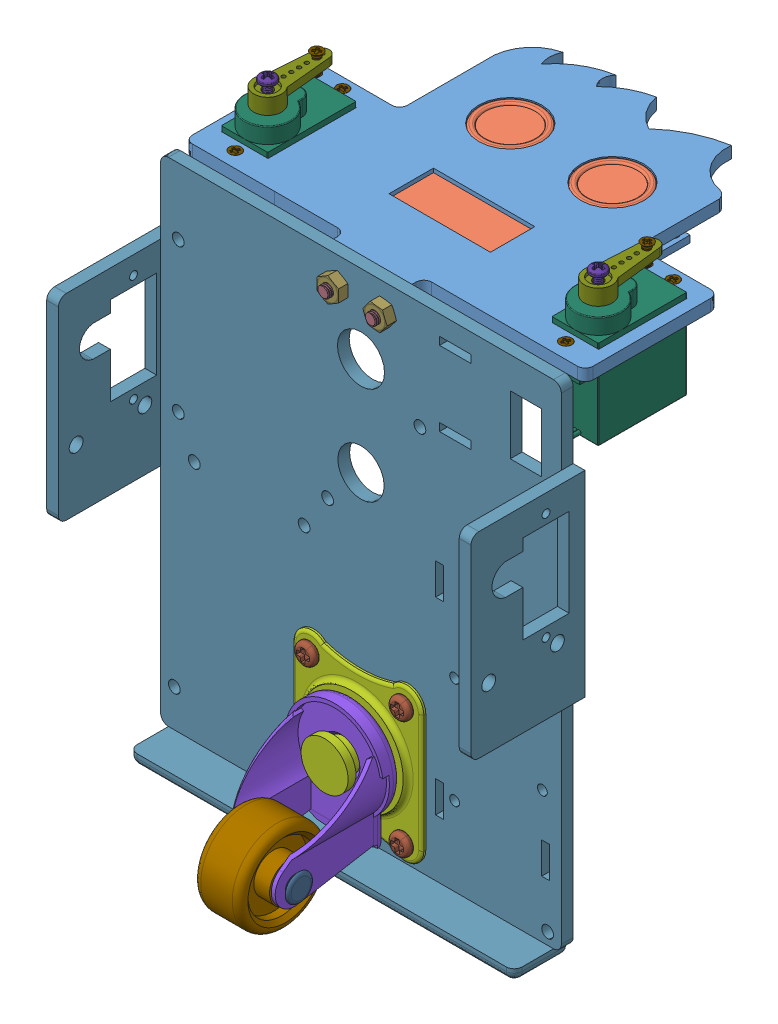
SolidWorks assembly DYOR_3D_OL_AC, configuration Predeterminado. Lengths in mm.
Overall size (108 144.05 112.97).
66 component instances, 23 part files, 16 mates.
Components (placement in the parent):
- HC-SR04 Ping Sensor-1: HC-SR04 Ping Sensor [Default] at (9.418 28.7888 -38.4615) x (0 0 -1) z (0 1 0) size (25.18 45 18.07)
  - PCB-1: PCB [Default] at origin size (20.5 45 1.75)
  - Transducer-1: Transducer [Default] at (0 -13 13.25) x (1 0 0) z (0 -1 0) size (15.88 12 15.88)
  - Transducer-2: Transducer [Default] at (0 13 13.25) x (1 0 0) z (0 -1 0) size (15.88 12 15.88)
  - 3 Pin Header 90 Degree-1: 3 Pin Header 90 Degree [Default] at (8.4275 0 -1.25) x (-1 0 0) z (0 -1 0) size (8 7.82 10)
  - 14 Pin SMT-1: 14 Pin SMT [Default] at (-0.35 -18.5 -0.85) x (0 -1 0) z (1 0 0) size (6 1.6 8.8)
  - 14 Pin SMT-2: 14 Pin SMT [Default] at (0 -0.3826 -0.85) x (1 0 0) z (0 1 0) size (6 1.6 8.8)
  - 14 Pin SMT-3: 14 Pin SMT [Default] at (0 17.5274 -0.85) x (1 0 0) z (0 1 0) size (6 1.6 8.8)
  - Cap1 SMT-1: Cap1 SMT [Default] at (-1.755 7.4774 -0.9689) x (0 1 0) z (-1 0 0) size (4.5 1.84 1.75)
  - Cap1 SMT-2: Cap1 SMT [Default] at (6.835 7.4774 -0.9689) x (0 1 0) z (-1 0 0) size (4.5 1.84 1.75)
  - Cap1 SMT-3: Cap1 SMT [Default] at (-6.835 7.4774 -0.9689) x (0 1 0) z (-1 0 0) size (4.5 1.84 1.75)
  - Cap1 SMT-4: Cap1 SMT [Default] at (4.295 7.4774 -0.9689) x (0 1 0) z (-1 0 0) size (4.5 1.84 1.75)
  - Cap1 SMT-5: Cap1 SMT [Default] at (1.755 7.4774 -0.9689) x (0 1 0) z (-1 0 0) size (4.5 1.84 1.75)
  - Cap1 SMT-6: Cap1 SMT [Default] at (-4.295 7.4774 -0.9689) x (0 1 0) z (-1 0 0) size (4.5 1.84 1.75)
  - HC-SR04 Crystal-1: HC-SR04 Crystal [Default] at (-8.3 0 1.75) x (0 -1 0) z (0 0 1) size (10 3.5 2.7)
- CA-1: CA [Predeterminado] at (-2.207 18.0036 0) size (33 45.94 43.2)
  - Caster Wheel-1: Caster Wheel [Default] at (57.6387 -78.841 57.7572) x (0 1 0) z (-1 0 0) size (45.94 37.59 33)
    - caster holder-1: caster holder [Default] at (-24.0751 44.7184 29.5137) x (1 0 0) z (0 0 -1) size (39 9.27 33)
    - holder-1: holder [Default] at (-1.5751 42.9484 46.0137) x (0 0 1) z (1 0 0) size (25 28.07 31.31)
    - caster wheel-1: caster wheel [Default] at (-15.6961 19.9484 46.0137) x (0.997275 0.073773 0) z (0 0 1) size (23 23 14)
    - Part4-1: Part4 [Default] at (-15.6961 19.9484 55.0137) x (-0.978448 0.206495 0) z (0 0 -1) size (7 7 20)
  - M3x6 Philips Screw-1: M3x6 Philips Screw [Predeterminado] at (23.625 -65.4161 13.5389) size (5.3 5.3 7.81)
  - M3x6 Philips Screw-2: M3x6 Philips Screw [Predeterminado] at (-0.375 -65.4161 13.5389) size (5.3 5.3 7.81)
  - M3x6 Philips Screw-3: M3x6 Philips Screw [Predeterminado] at (-0.375 -95.4161 13.5389) size (5.3 5.3 7.81)
  - M3x6 Philips Screw-4: M3x6 Philips Screw [Predeterminado] at (23.625 -95.4161 13.5389) size (5.3 5.3 7.81)
  - M3 Nut-1: M3 Nut [Predeterminado] at (23.625 -65.4161 11.0389) size (6.27 6.27 2.71)
  - M3 Nut-2: M3 Nut [Predeterminado] at (-0.375 -65.4161 11.0389) size (6.27 6.27 2.71)
  - M3 Nut-3: M3 Nut [Predeterminado] at (-0.375 -95.4161 11.0389) size (6.27 6.27 2.71)
  - M3 Nut-4: M3 Nut [Predeterminado] at (23.625 -95.4161 11.0389) size (6.27 6.27 2.71)
- M3x10 Philips Screw-2: M3x10 Philips Screw [Predeterminado] at (3.418 36.0388 6.1705) x (-0.582954 -0.812505 0) z (0 0 -1) size (5.3 5.3 11.8)
- M3x10 Philips Screw-3: M3x10 Philips Screw [Predeterminado] at (15.418 36.0388 6.1705) x (-0.89856 -0.438851 0) z (0 0 -1) size (5.3 5.3 11.8)
- M3 Nut-1: M3 Nut [Predeterminado] at (3.418 36.0388 16.5389) size (6.27 6.27 2.71)
- M3 Nut-2: M3 Nut [Predeterminado] at (15.418 36.0388 11.0389) x (-0.923728 -0.383049 0) z (0 0 -1) size (6.27 6.27 2.71)
- Base-1: Base [Predeterminado] at (60.418 -80.9125 12.5389) size (108 128.45 29)
- AC-1: AC [Predeterminado] at (-137.3228 216.8523 -134.1392) size (95.94 34.06 31.9)
  - sg90-1: sg90 [Default] at (182.9409 -195.7135 134.2781) x (0 0 -1) z (1 0 0) size (31.9 29.9 11.8)
  - sg90-2: sg90 [Default] at (98.7972 -195.7135 134.2781) x (0 0 -1) z (1 0 0) size (31.9 29.9 11.8)
  - SG90 plastic Horn-1: SG90 plastic Horn [Default] at (188.8409 -166.2635 128.3781) x (-0.029359 0 -0.999569) z (0.999569 0 -0.029359) size (19.4 4 7.07)
  - SG90 plastic Horn-2: SG90 plastic Horn [Default] at (104.6972 -166.2635 128.3781) x (-0.012387 0 -0.999923) z (0.999923 0 -0.012387) size (19.4 4 7.07)
  - (M2_3_mm)_90116A007_METRIC 316 SS PAN HEAD PHILLIPS MACHINE SCREW-1: (M2_3_mm)_90116A007_METRIC 316 SS PAN HEAD PHILLIPS MACHINE SCREW [90116A007] at (104.6972 -166.2635 128.3781) x (-1 0 0) z (0 1 0) size (4 4 4.68)
  - (M2_3_mm)_90116A007_METRIC 316 SS PAN HEAD PHILLIPS MACHINE SCREW-2: (M2_3_mm)_90116A007_METRIC 316 SS PAN HEAD PHILLIPS MACHINE SCREW [90116A007] at (188.8409 -166.2635 128.3781) x (-1 0 0) z (0 1 0) size (4 4 4.68)
  - M2x6 SelfTap Screw-1: M2x6 SelfTap Screw [Predeterminado] at (104.6972 -162.7635 115.8781) x (0.825172 0 -0.564882) z (0 1 0) size (3.4 3.28 6)
  - M2x6 SelfTap Screw-2: M2x6 SelfTap Screw [Predeterminado] at (188.7787 -162.7635 115.8783) x (0.001298 0 -0.999999) z (0 1 0) size (3.4 3.28 6)
  - M2x6 SelfTap Screw-3: M2x6 SelfTap Screw [Predeterminado] at (104.6972 -174.3135 109.3781) x (-0.923728 0 -0.383049) z (0 1 0) size (3.4 3.28 6)
  - M2x6 SelfTap Screw-4: M2x6 SelfTap Screw [Predeterminado] at (104.6972 -174.3135 136.6781) x (-0.923728 0 -0.383049) z (0 1 0) size (3.4 3.28 6)
  - M2x6 SelfTap Screw-5: M2x6 SelfTap Screw [Predeterminado] at (188.8409 -174.3135 136.6781) x (0.923728 0 0.383049) z (0 1 0) size (3.4 3.28 6)
  - M2x6 SelfTap Screw-6: M2x6 SelfTap Screw [Predeterminado] at (188.8409 -174.3135 109.3781) x (0.923728 0 0.383049) z (0 1 0) size (3.4 3.28 6)
- Front_OL_AC-1: Front_OL_AC [Predeterminado] at (-51.1718 39.5388 -46.4823) x (1 0 0) z (0 1 0) size (101.94 72.38 11)
- OLED_0.91_128x32-1: OLED_0.91_128x32 [Predeterminado] at (10.618 39.0288 -13.1554) x (1 0 0) z (0 1 0) size (38.3 12.1 11.46)
  - OLED_0.91_128x32.stp-1: OLED_0.91_128x32.stp [Predeterminado] at origin size (38.3 12.1 11.46)
    - OLED_0.91_128x32.stp-1: OLED_0.91_128x32.stp [Predeterminado] at origin size (38.3 12.1 2.57)
    - Pin Header 4 x 1 TH 2.54mm Pitch.stp-1: Pin Header 4 x 1 TH 2.54mm Pitch.stp [Predeterminado] at (-17.55 -3.81 -2.6) size (2.54 10.16 11.43)
    - RESC-0603.stp-1: RESC-0603.stp [Predeterminado] at (4.3 -5.3 0) x (1 0 0) z (0 0 -1) size (1.7 0.9 0.55)
    - RESC-0603.stp-2: RESC-0603.stp [Predeterminado] at (4.3 -3.8 0) x (1 0 0) z (0 0 -1) size (1.7 0.9 0.55)
    - RESC-0603.stp-3: RESC-0603.stp [Predeterminado] at (4.3 -2.3 0) x (1 0 0) z (0 0 -1) size (1.7 0.9 0.55)
    - RESC-0603.stp-4: RESC-0603.stp [Predeterminado] at (4.3 -0.8 0) x (1 0 0) z (0 0 -1) size (1.7 0.9 0.55)
    - RESC-0603.stp-5: RESC-0603.stp [Predeterminado] at (4.3 0.7 0) x (1 0 0) z (0 0 -1) size (1.7 0.9 0.55)
    - RESC-0603.stp-6: RESC-0603.stp [Predeterminado] at (4.3 2.2 0) x (1 0 0) z (0 0 -1) size (1.7 0.9 0.55)
    - RESC-0603.stp-7: RESC-0603.stp [Predeterminado] at (4.3 3.7 0) x (1 0 0) z (0 0 -1) size (1.7 0.9 0.55)
    - RESC-0603.stp-8: RESC-0603.stp [Predeterminado] at (4.3 5.2 0) x (1 0 0) z (0 0 -1) size (1.7 0.9 0.55)
    - RESC-0603.stp-9: RESC-0603.stp [Predeterminado] at (-1.4 -3.06 0) x (1 0 0) z (0 0 -1) size (1.7 0.9 0.55)
    - RESC-0603.stp-10: RESC-0603.stp [Predeterminado] at (-1.4 -1.56 0) x (1 0 0) z (0 0 -1) size (1.7 0.9 0.55)
    - RESC-0603.stp-11: RESC-0603.stp [Predeterminado] at (-1.4 -0.06 0) x (1 0 0) z (0 0 -1) size (1.7 0.9 0.55)
    - RESC-0603.stp-12: RESC-0603.stp [Predeterminado] at (-1.4 1.44 0) x (1 0 0) z (0 0 -1) size (1.7 0.9 0.55)
    - RESC-0603.stp-13: RESC-0603.stp [Predeterminado] at (-1.4 2.94 0) x (1 0 0) z (0 0 -1) size (1.7 0.9 0.55)
    - 2SD0601A.stp-1: 2SD0601A.stp [Predeterminado] at (-9.8 -1.3 -0.08) x (1 0 0) z (0 1 0) size (2.76 1.18 2.9)
Mates (geometry in assembly coordinates):
- Concéntrica15: concentric: circle of CA-1/Caster Wheel-1/caster holder-1; circle of Base-1
- Coincidente14: coincident: plane of CA-1/M3 Nut-4 through (21.418 -77.4125 9.5389) normal (0 0 1); plane of Base-1 through (-39.582 40.5388 9.5389) normal (0 0 -1)
- Concéntrica16: concentric: circle of CA-1/M3 Nut-1; circle of Base-1
- Coincidente26: coincident: plane of M3 Nut-2 through (15.418 36.0388 12.5389) normal (0 0 -1); plane of Base-1 through (-39.582 40.5388 12.5389) normal (0 0 1)
- Coincidente27: coincident: plane of M3 Nut-1 through (3.418 36.0388 12.5389) normal (0 0 -1); plane of Base-1 through (-39.582 40.5388 12.5389) normal (0 0 1)
- Concéntrica22: concentric: circle of M3 Nut-1; circle of Base-1
- Concéntrica23: concentric: circle of M3 Nut-2; circle of Base-1
- Coincidente28: coincident: plane of Base-1 through (-39.582 40.5388 9.5389) normal (0 0 -1); plane of Front_OL_AC-1 through (-0.582 42.5388 9.5389) normal (0 0 1)
- Concéntrica24: concentric: circle of Base-1; circle of Front_OL_AC-1
- Concéntrica25: concentric: circle of HC-SR04 Ping Sensor-1/Transducer-1; circle of Front_OL_AC-1
- Coincidente29: coincident: plane of HC-SR04 Ping Sensor-1/Transducer-1 through (22.418 42.5388 -46.4015) normal (0 1 0); plane of Front_OL_AC-1 through (-22.6447 42.5388 -29.3613) normal (0 1 0)
- Concéntrica26: concentric: circle of HC-SR04 Ping Sensor-1/Transducer-2; circle of Front_OL_AC-1
- Coincidente30: coincident: plane of Front_OL_AC-1 through (29.768 40.5388 -7.1054) normal (0 0 -1); plane of OLED_0.91_128x32-1/OLED_0.91_128x32.stp-1/OLED_0.91_128x32.stp-1 through (-8.532 39.0288 -7.1054) normal (0 0 1)
- Distancia1: distance = 1 mm: plane of OLED_0.91_128x32-1/OLED_0.91_128x32.stp-1/OLED_0.91_128x32.stp-1 through (9.418 41.5388 -13.1554) normal (0 1 0); plane of Front_OL_AC-1 through (-22.6447 42.5388 -29.3613) normal (0 1 0)
- Paralelo1: parallel: plane of Base-1 through (-39.582 42.5388 9.5389) normal (0 1 0); plane of Front_OL_AC-1 through (-22.6447 42.5388 -29.3613) normal (0 1 0)
- Coincidente36: coincident: plane of Front_OL_AC-1 through (-8.532 40.5388 -7.1054) normal (1 0 0); plane of OLED_0.91_128x32-1/OLED_0.91_128x32.stp-1/OLED_0.91_128x32.stp-1 through (-8.532 39.0288 -19.2054) normal (-1 0 0)
